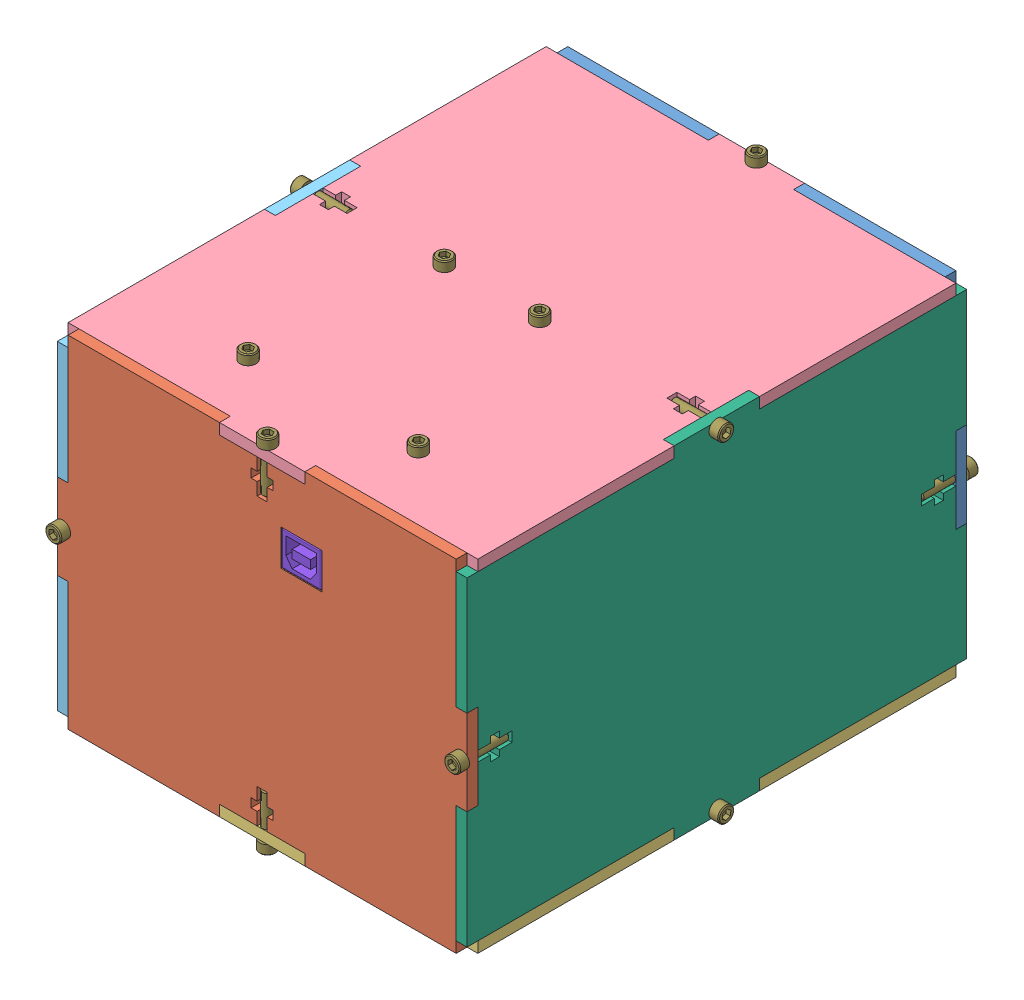
SolidWorks assembly PIDBoxAssem, configuration Default. Lengths in mm.
Overall size (127.39 117.77 152.04).
67 component instances, 23 part files, 145 mates.
Components (placement in the parent):
- PIDBoxFrontWall-1: PIDBoxFrontWall [Default] at (35.9834 39.6411 54.7935) size (120 100 3.17)
- PIDBoxBackWall-1: PIDBoxBackWall [Default] at (35.9834 39.6411 197.9685) size (120 100 3.17)
- PIDBoxTopWall-1: PIDBoxTopWall [Default] at (35.9834 -8.7714 126.381) x (0 0 -1) z (0 1 0) size (146.35 120 3.17)
- PIDBoxBottomWall-1: PIDBoxBottomWall [Default] at (35.9834 88.0536 126.381) x (0 0 1) z (0 -1 0) size (146.35 120 3.17)
- PIDBoxLeftWall-1: PIDBoxLeftWall [Default] at (-22.4291 39.6411 126.381) x (0 -1 0) z (-1 0 0) size (100 146.35 3.17)
- PIDBoxRightWall-1: PIDBoxRightWall [Default] at (94.3959 39.6411 126.381) x (0 1 0) z (-1 0 0) size (100 146.35 3.17)
- BatteryPack-1: BatteryPack [Default] at (-6.9166 43.4661 122.381) x (0 0 1) z (-1 0 0) size (104 66 18.8)
- ArduinoUno-1: ArduinoUno [Default] at (35.8084 73.7661 160.356) x (0 0 -1) z (-1 0 0) size (74.8 12.1 53.3)
- EE-SX672WR-1: EE-SX672WR [Default] at (60.4834 42.2161 69.081) x (0 0 -1) z (-1 0 0) size (13.7 38.4 26)
- MotorAssem-1: MotorAssem [Default] at (11.9922 -30.4605 140.9197) x (0 1 0) z (0 0 -1) size (63.22 63.17 37.75)
  - MotorMount-1: MotorMount [Default] at (15.7766 38.9912 50.9262) size (24 52.9 6)
  - DCmotor-Size130-1: DCmotor-Size130 [Default] at (36.7766 38.9912 34.9262) size (16.47 19.75 37.75)
  - socket head cap screw_ai-11: socket head cap screw_ai [HX-SHCS 0.112-40x0.625x0.625-N] at (50.1214 55.2437 53.9262) x (-1 0 0) z (0 0.924225 0.381849) size (18.72 4.65 4.65)
  - socket head cap screw_ai-12: socket head cap screw_ai [HX-SHCS 0.112-40x0.625x0.625-N] at (50.1214 22.7387 53.9262) x (-1 0 0) z (0 0.924225 0.381849) size (18.72 4.65 4.65)
  - InterruptWheel-1: InterruptWheel [Default] at (36.7766 38.9912 64.8387) x (0.948715 0.316133 0) z (0 0 1) size (50 49.92 3.17)
- 16x2 LCD Screen and Backpack-2: 16x2 LCD Screen and Backpack [Default] at (50.9834 -7.6283 151.1628) x (1 0 0) z (0 0 -1) size (80 20.27 36)
  - LCD_PCB-1: LCD_PCB [Default] at (-1.4055 -3.4444 3.0818) size (80 1.8 36)
  - metal_casing-1: metal_casing [Default] at (-1.5055 3.0556 3.5818) size (71.2 10.64 25.26)
  - LCDbacklight-1: LCDbacklight [Default] at (-1.7555 -3.4444 3.5818) size (74.7 3 18)
  - LCD-1: LCD [Default] at (-1.6055 1.9556 3.5818) size (70.3 2.1 22)
  - conductors-1: conductors [Default] at (-1.7555 -0.6944 13.8318) size (69.7 5.5 2.5)
  - conductors-2: conductors [Default] at (-1.7555 -0.6944 -6.6682) size (69.7 5.5 2.5)
  - LCD Backpack-1: LCD Backpack [Default] at (-14.7555 -9.9444 -4.3182) x (-1 0 0) z (0 -1 0) size (52 19.3 15.37)
- Panel Mount 10k Potentiometer-1: Panel Mount 10k Potentiometer [Default] at (50.9834 -7.1839 118.8352) x (0 -1 0) z (0 0 1) size (23.57 25.5 17)
- Panel Mount SPDT-1: Panel Mount SPDT [Default] at (74.1447 2.7261 102.731) x (-1 0 0) z (0 0 1) size (8 31.74 12.7)
- Panel Mount SPDT-2: Panel Mount SPDT [Default] at (27.8222 2.7261 102.731) x (-1 0 0) z (0 0 1) size (8 31.74 12.7)
- Panel Mount LED-2: Panel Mount LED [Default] at (-4.0166 -0.3589 156.381) x (-0.837169 0 -0.546944) z (-0.546944 0 0.837169) size (11.13 16 10.04)
- Panel Mount LED-3: Panel Mount LED [Default] at (-4.0166 -0.3589 136.381) x (-0.497225 0 -0.867621) z (-0.867621 0 0.497225) size (11.13 16 10.04)
- Panel Mount LED-4: Panel Mount LED [Default] at (-4.0166 -0.3589 116.381) x (-0.837169 0 -0.546944) z (-0.546944 0 0.837169) size (11.13 16 10.04)
- Panel Mount LED-5: Panel Mount LED [Default] at (-4.0166 -0.3589 96.381) x (-0.438178 0 -0.898888) z (-0.898888 0 0.438178) size (11.13 16 10.04)
- Panel Mount LED-6: Panel Mount LED [Default] at (-4.0166 -0.3589 76.381) x (-0.970279 0 -0.241991) z (-0.241991 0 0.970279) size (11.13 16 10.04)
- Panel Mount LED-9: Panel Mount LED [Default] at (74.1447 -0.3589 118.8352) x (-1 0 0) z (0 0 1) size (11.13 16 10.04)
- Panel Mount LED-10: Panel Mount LED [Default] at (27.8222 -0.3589 118.8352) x (-1 0 0) z (0 0 1) size (11.13 16 10.04)
- 25x.5 Aluminum Hex Female Female Standoff-1: 25x.5 Aluminum Hex Female Female Standoff [Default] at (40.5834 42.2161 62.731) x (0.999498 0.031674 0) z (0 0 1) size (6.35 8.06 12.7)
- 25x.5 Aluminum Hex Female Female Standoff-2: 25x.5 Aluminum Hex Female Female Standoff [Default] at (61.3834 42.2161 62.731) x (0.973982 0.226625 0) z (0 0 1) size (6.35 8.06 12.7)
- 25x.5 Aluminum Hex Female Female Standoff-3: 25x.5 Aluminum Hex Female Female Standoff [Default] at (11.6584 80.1161 179.356) x (1 0 0) z (0 -1 0) size (6.35 8.06 12.7)
- 25x.5 Aluminum Hex Female Female Standoff-4: 25x.5 Aluminum Hex Female Female Standoff [Default] at (16.7584 80.1161 126.956) x (1 0 0) z (0 -1 0) size (6.35 8.06 12.7)
- 25x.5 Aluminum Hex Female Female Standoff-5: 25x.5 Aluminum Hex Female Female Standoff [Default] at (44.6584 80.1161 126.956) x (1 0 0) z (0 -1 0) size (6.35 8.06 12.7)
- 25x.5 Aluminum Hex Female Female Standoff-7: 25x.5 Aluminum Hex Female Female Standoff [Default] at (59.9584 80.1161 177.756) x (1 0 0) z (0 -1 0) size (6.35 8.06 12.7)
- socket head cap screw_ai-3: socket head cap screw_ai [HX-SHCS 0.112-40x0.5x0.5-N] at (74.1447 -13.2037 86.9935) x (0 1 0) z (0 0 1) size (15.54 4.65 4.65)
- socket head cap screw_ai-4: socket head cap screw_ai [HX-SHCS 0.112-40x0.5x0.5-N] at (27.8222 -13.2037 86.9935) x (0 1 0) z (0 0 1) size (15.54 4.65 4.65)
- socket head cap screw_ai-2: socket head cap screw_ai [HX-SHCS 0.112-40x0.5x0.5-N] at (87.0779 -13.2037 163.581) x (0 1 0) z (0 0 1) size (15.54 4.65 4.65)
- socket head cap screw_ai-5: socket head cap screw_ai [HX-SHCS 0.112-40x0.5x0.5-N] at (87.0779 -13.2037 132.581) x (0 1 0) z (0 0 1) size (15.54 4.65 4.65)
- socket head cap screw_ai-6: socket head cap screw_ai [HX-SHCS 0.112-40x0.5x0.5-N] at (12.0779 -13.2037 132.581) x (0 1 0) z (0 0 1) size (15.54 4.65 4.65)
- socket head cap screw_ai-7: socket head cap screw_ai [HX-SHCS 0.112-40x0.5x0.5-N] at (12.0779 -13.2037 163.581) x (0 1 0) z (0 0 1) size (15.54 4.65 4.65)
- socket head cap screw_ai-9: socket head cap screw_ai [HX-SHCS 0.112-40x0.5x0.5-N] at (61.3834 42.2161 50.3612) x (0 0 1) z (-1 0 0) size (15.54 4.65 4.65)
- socket head cap screw_ai-10: socket head cap screw_ai [HX-SHCS 0.112-40x0.5x0.5-N] at (40.5834 42.2161 50.3612) x (0 0 1) z (-1 0 0) size (15.54 4.65 4.65)
- socket head cap screw_ai-11: socket head cap screw_ai [HX-SHCS 0.112-40x0.5x0.5-N] at (61.3834 42.2161 74.9258) x (0 0 -1) z (1 0 0) size (15.54 4.65 4.65)
- socket head cap screw_ai-12: socket head cap screw_ai [HX-SHCS 0.112-40x0.5x0.5-N] at (40.5834 42.2161 74.9258) x (0 0 -1) z (1 0 0) size (15.54 4.65 4.65)
- socket head cap screw_ai-17: socket head cap screw_ai [HX-SHCS 0.112-40x0.5x0.5-N] at (-28.5614 23.4661 175.381) size (15.54 4.65 4.65)
- socket head cap screw_ai-18: socket head cap screw_ai [HX-SHCS 0.112-40x0.5x0.5-N] at (-28.5614 63.4661 175.381) size (15.54 4.65 4.65)
- socket head cap screw_ai-20: socket head cap screw_ai [HX-SHCS 0.112-40x0.5x0.5-N] at (94.3959 39.6411 50.3612) x (0 0 1) z (-1 0 0) size (15.54 4.65 4.65)
- socket head cap screw_ai-21: socket head cap screw_ai [HX-SHCS 0.112-40x0.5x0.5-N] at (35.9834 -13.2037 54.7935) x (0 1 0) z (0 0 1) size (15.54 4.65 4.65)
- socket head cap screw_ai-22: socket head cap screw_ai [HX-SHCS 0.112-40x0.5x0.5-N] at (35.9834 92.4859 54.7935) x (0 -1 0) z (0 0 1) size (15.54 4.65 4.65)
- socket head cap screw_ai-23: socket head cap screw_ai [HX-SHCS 0.112-40x0.5x0.5-N] at (16.7584 92.4859 126.956) x (0 -1 0) z (0 0 1) size (15.54 4.65 4.65)
- socket head cap screw_ai-24: socket head cap screw_ai [HX-SHCS 0.112-40x0.5x0.5-N] at (44.6584 92.4859 126.956) x (0 -1 0) z (0 0 1) size (15.54 4.65 4.65)
- socket head cap screw_ai-25: socket head cap screw_ai [HX-SHCS 0.112-40x0.5x0.5-N] at (59.9584 92.4859 177.756) x (0 -1 0) z (0 0 1) size (15.54 4.65 4.65)
- socket head cap screw_ai-26: socket head cap screw_ai [HX-SHCS 0.112-40x0.5x0.5-N] at (11.6584 92.4859 179.356) x (0 -1 0) z (0 0 1) size (15.54 4.65 4.65)
- socket head cap screw_ai-27: socket head cap screw_ai [HX-SHCS 0.112-40x0.5x0.5-N] at (35.9834 92.4859 197.9685) x (0 -1 0) z (0 0 1) size (15.54 4.65 4.65)
- socket head cap screw_ai-28: socket head cap screw_ai [HX-SHCS 0.112-40x0.5x0.5-N] at (98.8282 88.0536 126.381) x (-1 0 0) z (0 0.924225 0.381849) size (15.54 4.65 4.65)
- socket head cap screw_ai-29: socket head cap screw_ai [HX-SHCS 0.112-40x0.5x0.5-N] at (98.8282 -8.7714 126.381) x (-1 0 0) z (0 0.924225 0.381849) size (15.54 4.65 4.65)
- socket head cap screw_ai-30: socket head cap screw_ai [HX-SHCS 0.112-40x0.5x0.5-N] at (94.3959 39.6411 202.4008) x (0 0 -1) z (1 0 0) size (15.54 4.65 4.65)
- socket head cap screw_ai-31: socket head cap screw_ai [HX-SHCS 0.112-40x0.5x0.5-N] at (35.9834 -13.2037 197.9685) x (0 1 0) z (0 0 1) size (15.54 4.65 4.65)
- socket head cap screw_ai-32: socket head cap screw_ai [HX-SHCS 0.112-40x0.5x0.5-N] at (-22.4291 39.6411 202.4008) x (0 0 -1) z (1 0 0) size (15.54 4.65 4.65)
- socket head cap screw_ai-33: socket head cap screw_ai [HX-SHCS 0.112-40x0.5x0.5-N] at (-26.8614 88.0536 126.381) size (15.54 4.65 4.65)
- socket head cap screw_ai-34: socket head cap screw_ai [HX-SHCS 0.112-40x0.5x0.5-N] at (-26.8614 -8.7714 126.381) size (15.54 4.65 4.65)
- socket head cap screw_ai-35: socket head cap screw_ai [HX-SHCS 0.112-40x0.5x0.5-N] at (-22.4291 39.6411 50.3612) x (0 0 1) z (-1 0 0) size (15.54 4.65 4.65)
Mates (geometry in assembly coordinates):
- Coincident1: coincident aligned: plane of PIDBoxWall1-1 through (35.9834 39.6411 53.206) normal (0 0 -1); plane of PIDBoxTopWall-1 through (23.4834 -7.1839 53.206) normal (0 0 -1)
- Parallel1: parallel aligned: plane of PIDBoxWall1-1 through (35.9834 89.6411 56.381) normal (0 1 0); plane of PIDBoxTopWall-1 through (35.9834 -7.1839 126.381) normal (0 1 0)
- Coincident3: coincident aligned: line of PIDBoxWall1-1 through (48.4834 -10.3589 56.381) axis (1 0 0); line of PIDBoxTopWall-1 through (48.4834 -10.3589 56.381) axis (1 0 0)
- Coincident4: coincident: line of PIDBoxWall1-1 through (23.4834 -7.1839 56.381) axis (0 0 -1); plane of PIDBoxTopWall-1 through (23.4834 -7.1839 53.206) normal (-1 0 0)
- Coincident5: coincident anti-aligned: plane of PIDBoxTopWall-1 through (35.9834 -7.1839 126.381) normal (0 1 0); plane of MotorAssem-1/MotorMount-1 through (50.9834 -7.1839 89.9935) normal (0 -1 0)
- Distance3: distance = 15 mm anti-aligned: plane of PIDBoxTopWall-1 through (35.9834 -8.7714 126.381) normal (-1 0 0); plane of MotorAssem-1/DCmotor-Size130-1 through (50.9834 6.3161 105.9935) normal (1 0 0)
- Parallel2: parallel anti-aligned: plane of PIDBoxTopWall-1 through (35.9834 -10.3589 126.381) normal (0 -1 0); plane of EE-SX672WR-1 through (47.8084 52.5161 73.581) normal (0 1 0)
- Distance4: distance = 15 mm: point of PIDBoxWall1-1; moEndPointRef_w of EE-SX672WR-1
- Concentric1: concentric aligned: circle of 25x.5 Aluminum Hex Female Female Standoff-1; circle of EE-SX672WR-1
- Coincident10: coincident anti-aligned: plane of EE-SX672WR-1 through (60.4834 42.2161 69.081) normal (0 0 -1); plane of 25x.5 Aluminum Hex Female Female Standoff-1 through (40.5834 42.2161 69.081) normal (0 0 1)
- Coincident11: coincident anti-aligned: plane of PIDBoxWall1-1 through (35.9834 39.6411 56.381) normal (0 0 1); plane of 25x.5 Aluminum Hex Female Female Standoff-1 through (40.5834 42.2161 56.381) normal (0 0 -1)
- Concentric2: concentric aligned: circle of EE-SX672WR-1; circle of 25x.5 Aluminum Hex Female Female Standoff-2
- Coincident12: coincident anti-aligned: plane of EE-SX672WR-1 through (60.4834 42.2161 69.081) normal (0 0 -1); plane of 25x.5 Aluminum Hex Female Female Standoff-2 through (61.3834 42.2161 69.081) normal (0 0 1)
- Coincident17: coincident: plane of MotorAssem-1/InterruptWheel-1 through (50.9834 6.3161 76.081) normal (0 0 -1); line of EE-SX672WR-1 through (54.1584 35.3161 76.081) axis (0 1 0)
- Distance1: distance = 4 mm anti-aligned: plane of EE-SX672WR-1 through (54.1584 35.3161 78.581) normal (0 -1 0); cylinder of MotorAssem-1/InterruptWheel-1 through (50.9834 6.3161 74.4935) axis (0 0 1) radius 25
- Coincident24: coincident anti-aligned: plane of PIDBoxTopWall-1 through (35.9834 -7.1839 126.381) normal (0 1 0); plane of 16x2 LCD Screen and Backpack-2/LCDbacklight-1 through (49.2279 -7.1839 147.581) normal (0 -1 0)
- Parallel7: parallel anti-aligned: plane of PIDBoxWall1-1 through (35.9834 39.6411 56.381) normal (0 0 1); plane of 16x2 LCD Screen and Backpack-2/LCD_PCB-1 through (89.5779 -2.5839 130.081) normal (0 0 -1)
- Distance6: distance = 15 mm aligned: plane of PIDBoxWall1-1 through (35.9834 39.6411 54.7935) normal (1 0 0); plane of 16x2 LCD Screen and Backpack-2 through (50.9834 -7.6283 151.1628) normal (1 0 0)
- Distance2: distance = 50 mm aligned: plane of 16x2 LCD Screen and Backpack-2/LCD_PCB-1 through (89.5779 -2.5839 130.081) normal (0 0 -1); plane of PIDBoxTopWall-1 through (28.4834 -7.1839 80.081) normal (0 0 -1)
- Parallel8: parallel anti-aligned: plane of PIDBoxTopWall-1 through (35.9834 -10.3589 126.381) normal (0 -1 0); plane of Panel Mount 10k Potentiometer-1 through (50.9834 0.3161 118.8352) normal (0 1 0)
- Parallel9: parallel aligned: plane of PIDBoxWall1-1 through (35.9834 39.6411 53.206) normal (0 0 -1); plane of Panel Mount 10k Potentiometer-1 through (47.7334 -16.6839 113.206) normal (0 0 -1)
- Distance5: distance = 15 mm anti-aligned: plane of PIDBoxTopWall-1 through (35.9834 -8.7714 126.381) normal (-1 0 0); plane of Panel Mount 10k Potentiometer-1 through (50.9834 -7.1839 118.8352) normal (1 0 0)
- Coincident30: coincident anti-aligned: plane of PIDBoxTopWall-1 through (35.9834 -7.1839 126.381) normal (0 1 0); plane of Panel Mount 10k Potentiometer-1 through (50.9834 -7.1839 118.8352) normal (0 -1 0)
- Concentric3: concentric anti-aligned: circle of PIDBoxWall2-1; cylinder of Panel Mount LED-2 through (-4.0166 -0.3589 156.381) axis (0 1 0) radius 3.937
- Coincident34: coincident anti-aligned: plane of PIDBoxTopWall-1 through (35.9834 -10.3589 126.381) normal (0 -1 0); plane of Panel Mount LED-2 through (-8.2198 -10.3589 153.635) normal (0 1 0)
- Concentric4: concentric anti-aligned: cylinder of PIDBoxTopWall-1 through (-4.0166 -7.1839 136.381) axis (0 -1 0) radius 4; cylinder of Panel Mount LED-3 through (-4.0166 -0.3589 136.381) axis (0 1 0) radius 3.937
- Coincident35: coincident anti-aligned: plane of PIDBoxTopWall-1 through (35.9834 -10.3589 126.381) normal (0 -1 0); plane of Panel Mount LED-3 through (-6.513 -10.3589 132.025) normal (0 1 0)
- Coincident38: coincident anti-aligned: plane of PIDBoxTopWall-1 through (35.9834 -10.3589 126.381) normal (0 -1 0); plane of Panel Mount LED-4 through (-8.2198 -10.3589 113.635) normal (0 1 0)
- Coincident39: coincident anti-aligned: plane of PIDBoxTopWall-1 through (35.9834 -10.3589 126.381) normal (0 -1 0); plane of Panel Mount LED-5 through (-6.2166 -10.3589 91.868) normal (0 1 0)
- Concentric5: concentric anti-aligned: cylinder of PIDBoxTopWall-1 through (-4.0166 -7.1839 116.381) axis (0 -1 0) radius 4; cylinder of Panel Mount LED-4 through (-4.0166 -0.3589 116.381) axis (0 1 0) radius 3.937
- Concentric6: concentric anti-aligned: cylinder of PIDBoxTopWall-1 through (-4.0166 -7.1839 96.381) axis (0 -1 0) radius 4; cylinder of Panel Mount LED-5 through (-4.0166 -0.3589 96.381) axis (0 1 0) radius 3.937
- Coincident40: coincident anti-aligned: plane of PIDBoxTopWall-1 through (35.9834 -10.3589 126.381) normal (0 -1 0); plane of Panel Mount LED-6 through (-8.8881 -10.3589 75.1661) normal (0 1 0)
- Concentric7: concentric anti-aligned: cylinder of PIDBoxTopWall-1 through (-4.0166 -7.1839 76.381) axis (0 -1 0) radius 4; cylinder of Panel Mount LED-6 through (-4.0166 -0.3589 76.381) axis (0 1 0) radius 3.937
- Distance7: distance = 60 mm aligned: plane of Panel Mount 10k Potentiometer-1 through (47.7334 -16.6839 113.206) normal (0 0 -1); plane of PIDBoxWall1-1 through (35.9834 39.6411 53.206) normal (0 0 -1)
- Concentric8: concentric anti-aligned: cylinder of PIDBoxTopWall-1 through (87.0779 -10.3589 163.581) axis (0 1 0) radius 1.25; cylinder of socket head cap screw_ai-2 through (87.0779 -44.9537 163.581) axis (0 -1 0) radius 2.3241
- Coincident41: coincident anti-aligned: plane of PIDBoxTopWall-1 through (35.9834 -10.3589 126.381) normal (0 -1 0); plane of socket head cap screw_ai-2 through (84.7538 -10.3589 163.581) normal (0 1 0)
- Concentric9: concentric anti-aligned: cylinder of PIDBoxTopWall-1 through (74.1447 -10.3589 86.9935) axis (0 1 0) radius 1.47; cylinder of socket head cap screw_ai-3 through (74.1447 -44.9537 86.9935) axis (0 -1 0) radius 2.3241
- Coincident42: coincident anti-aligned: plane of PIDBoxTopWall-1 through (35.9834 -10.3589 126.381) normal (0 -1 0); plane of socket head cap screw_ai-3 through (71.8206 -10.3589 86.9935) normal (0 1 0)
- Concentric10: concentric anti-aligned: cylinder of PIDBoxTopWall-1 through (27.8222 -10.3589 86.9935) axis (0 1 0) radius 1.47; cylinder of socket head cap screw_ai-4 through (27.8222 -44.9537 86.9935) axis (0 -1 0) radius 2.3241
- Coincident43: coincident anti-aligned: plane of PIDBoxTopWall-1 through (35.9834 -10.3589 126.381) normal (0 -1 0); plane of socket head cap screw_ai-4 through (25.4981 -10.3589 86.9935) normal (0 1 0)
- Concentric11: concentric anti-aligned: cylinder of PIDBoxTopWall-1 through (87.0779 -10.3589 132.581) axis (0 1 0) radius 1.25; cylinder of socket head cap screw_ai-5 through (87.0779 -44.9537 132.581) axis (0 -1 0) radius 2.3241
- Coincident44: coincident anti-aligned: plane of PIDBoxTopWall-1 through (35.9834 -10.3589 126.381) normal (0 -1 0); plane of socket head cap screw_ai-5 through (84.7538 -10.3589 132.581) normal (0 1 0)
- Concentric12: concentric anti-aligned: cylinder of PIDBoxTopWall-1 through (12.0779 -10.3589 132.581) axis (0 1 0) radius 1.25; cylinder of socket head cap screw_ai-6 through (12.0779 -44.9537 132.581) axis (0 -1 0) radius 2.3241
- Coincident45: coincident anti-aligned: plane of PIDBoxTopWall-1 through (35.9834 -10.3589 126.381) normal (0 -1 0); plane of socket head cap screw_ai-6 through (9.7538 -10.3589 132.581) normal (0 1 0)
- Concentric13: concentric anti-aligned: cylinder of PIDBoxTopWall-1 through (12.0779 -10.3589 163.581) axis (0 1 0) radius 1.25; cylinder of socket head cap screw_ai-7 through (12.0779 -44.9537 163.581) axis (0 -1 0) radius 2.3241
- Coincident46: coincident anti-aligned: plane of PIDBoxTopWall-1 through (35.9834 -10.3589 126.381) normal (0 -1 0); plane of socket head cap screw_ai-7 through (9.7538 -10.3589 163.581) normal (0 1 0)
- Coincident47: coincident anti-aligned: plane of PIDBoxTopWall-1 through (35.9834 -7.1839 126.381) normal (0 1 0); plane of Panel Mount SPDT-1 through (74.1447 -7.1839 102.731) normal (0 -1 0)
- Parallel10: parallel aligned: plane of PIDBoxWall1-1 through (35.9834 39.6411 56.381) normal (0 0 1); plane of Panel Mount SPDT-1 through (77.5747 -6.1639 109.081) normal (0 0 1)
- Coincident49: coincident anti-aligned: plane of PIDBoxTopWall-1 through (35.9834 -7.1839 126.381) normal (0 1 0); plane of Panel Mount SPDT-2 through (27.8222 -7.1839 102.731) normal (0 -1 0)
- Parallel11: parallel anti-aligned: plane of PIDBoxWall1-1 through (35.9834 39.6411 56.381) normal (0 0 1); plane of Panel Mount SPDT-2 through (31.2522 -6.1639 96.381) normal (0 0 -1)
- Coincident52: coincident: plane of Panel Mount SPDT-2 through (27.8222 2.7261 102.731) normal (-1 0 0)
- Coincident53: coincident: plane of Panel Mount SPDT-1 through (74.1447 2.7261 102.731) normal (-1 0 0)
- Distance8: distance = 40 mm anti-aligned: plane of Panel Mount SPDT-2 through (31.2522 -6.1639 96.381) normal (0 0 -1); plane of PIDBoxWall1-1 through (35.9834 39.6411 56.381) normal (0 0 1)
- Coincident55: coincident aligned: plane of Panel Mount SPDT-1 through (77.5747 -6.1639 96.381) normal (0 0 -1); plane of Panel Mount SPDT-2 through (31.2522 -6.1639 96.381) normal (0 0 -1)
- Coincident56: coincident aligned: plane of Panel Mount SPDT-2 through (27.8222 2.7261 102.731) normal (-1 0 0); plane of Panel Mount LED-10 through (27.8222 -0.3589 118.8352) normal (-1 0 0)
- Coincident57: coincident aligned: plane of Panel Mount SPDT-1 through (74.1447 2.7261 102.731) normal (-1 0 0); plane of Panel Mount LED-9 through (74.1447 -0.3589 118.8352) normal (-1 0 0)
- Coincident58: coincident anti-aligned: plane of PIDBoxTopWall-1 through (35.9834 -10.3589 126.381) normal (0 -1 0); plane of Panel Mount LED-10 through (22.8015 -10.3589 118.8352) normal (0 1 0)
- Coincident59: coincident anti-aligned: plane of PIDBoxTopWall-1 through (35.9834 -10.3589 126.381) normal (0 -1 0); plane of Panel Mount LED-9 through (69.124 -10.3589 118.8352) normal (0 1 0)
- Coincident60: coincident aligned: plane of Panel Mount LED-9 through (74.1447 -0.3589 118.8352) normal (0 0 1); plane of Panel Mount 10k Potentiometer-1 through (50.9834 -7.1839 118.8352) normal (0 0 1)
- Coincident61: coincident aligned: plane of Panel Mount 10k Potentiometer-1 through (50.9834 -7.1839 118.8352) normal (0 0 1); plane of Panel Mount LED-10 through (27.8222 -0.3589 118.8352) normal (0 0 1)
- Concentric14: concentric aligned: cylinder of PIDBoxWall1-1 through (61.3834 42.2161 56.381) axis (0 0 -1) radius 1.0287; cylinder of socket head cap screw_ai-9 through (61.3834 42.2161 18.6112) axis (0 0 -1) radius 2.3241
- Coincident62: coincident anti-aligned: plane of PIDBoxWall1-1 through (35.9834 39.6411 53.206) normal (0 0 -1); plane of socket head cap screw_ai-9 through (61.3834 44.5402 53.206) normal (0 0 1)
- Concentric151: concentric aligned: cylinder of PIDBoxWall1-1 through (40.5834 42.2161 56.381) axis (0 0 -1) radius 1.0287; cylinder of socket head cap screw_ai-10 through (40.5834 42.2161 18.6112) axis (0 0 -1) radius 2.3241
- Coincident631: coincident anti-aligned: plane of PIDBoxWall1-1 through (35.9834 39.6411 53.206) normal (0 0 -1); plane of socket head cap screw_ai-10 through (40.5834 44.5402 53.206) normal (0 0 1)
- Concentric16: concentric anti-aligned: cylinder of EE-SX672WR-1 through (61.3834 42.2161 82.781) axis (0 0 -1) radius 1.6; cylinder of socket head cap screw_ai-11 through (61.3834 42.2161 106.6758) axis (0 0 1) radius 2.3241
- Coincident64: coincident anti-aligned: plane of EE-SX672WR-1 through (63.9834 39.1161 72.081) normal (0 0 1); plane of socket head cap screw_ai-11 through (61.3834 44.5402 72.081) normal (0 0 -1)
- Concentric17: concentric aligned: cylinder of EE-SX672WR-1 through (40.5834 42.2161 69.081) axis (0 0 1) radius 1.6; cylinder of socket head cap screw_ai-12 through (40.5834 42.2161 106.6758) axis (0 0 1) radius 2.3241
- Coincident65: coincident anti-aligned: plane of EE-SX672WR-1 through (37.9834 45.3161 72.081) normal (0 0 1); plane of socket head cap screw_ai-12 through (40.5834 44.5402 72.081) normal (0 0 -1)
- Coincident66: coincident anti-aligned: plane of PIDBoxWall1-1 through (35.9834 39.6411 56.381) normal (0 0 1); plane of PIDBoxBottomWall-1 through (35.9834 86.4661 56.381) normal (0 0 -1)
- Coincident67: coincident anti-aligned: line of PIDBoxWall1-1 through (34.5134 86.4661 53.206) axis (-1 0 0); line of PIDBoxBottomWall-1 through (23.4834 86.4661 53.206) axis (1 0 0)
- Coincident68: coincident anti-aligned: plane of PIDBoxWall1-1 through (48.4834 39.6411 56.381) normal (-1 0 0); plane of PIDBoxBottomWall-1 through (48.4834 86.4661 53.206) normal (1 0 0)
- Parallel12: parallel anti-aligned: plane of PIDBoxBottomWall-1 through (35.9834 86.4661 126.381) normal (0 -1 0); plane of ArduinoUno-1 through (62.4584 73.7661 127.356) normal (0 1 0)
- Concentric18: concentric anti-aligned: circle of ArduinoUno-1; circle of 25x.5 Aluminum Hex Female Female Standoff-3
- Coincident70: coincident anti-aligned: plane of ArduinoUno-1 through (62.4584 73.7661 127.356) normal (0 1 0); plane of 25x.5 Aluminum Hex Female Female Standoff-3 through (11.6584 73.7661 179.356) normal (0 -1 0)
- Coincident71: coincident aligned: circle of ArduinoUno-1; plane of 25x.5 Aluminum Hex Female Female Standoff-4 through (16.7584 73.7661 126.956) normal (0 -1 0)
- Concentric19: concentric aligned: circle of ArduinoUno-1; circle of 25x.5 Aluminum Hex Female Female Standoff-4
- Coincident72: coincident anti-aligned: plane of ArduinoUno-1 through (62.4584 73.7661 127.356) normal (0 1 0); plane of 25x.5 Aluminum Hex Female Female Standoff-5 through (44.6584 73.7661 126.956) normal (0 -1 0)
- Concentric20: concentric anti-aligned: circle of ArduinoUno-1; circle of 25x.5 Aluminum Hex Female Female Standoff-5
- Coincident74: coincident anti-aligned: plane of ArduinoUno-1 through (62.4584 73.7661 127.356) normal (0 1 0); plane of 25x.5 Aluminum Hex Female Female Standoff-7 through (59.9584 73.7661 177.756) normal (0 -1 0)
- Concentric22: concentric aligned: circle of ArduinoUno-1; circle of 25x.5 Aluminum Hex Female Female Standoff-7
- Coincident632: coincident aligned: plane of PIDBoxTopWall-1 through (23.4834 -7.1839 199.556) normal (0 0 1); plane of PIDBoxBackWall-1 through (35.9834 39.6411 199.556) normal (0 0 1)
- Coincident633: coincident anti-aligned: plane of PIDBoxBottomWall-1 through (48.4834 86.4661 199.556) normal (1 0 0); plane of PIDBoxBackWall-1 through (48.4834 39.6411 199.556) normal (-1 0 0)
- Coincident634: coincident anti-aligned: plane of PIDBoxBottomWall-1 through (35.9834 86.4661 126.381) normal (0 -1 0); plane of PIDBoxBackWall-1 through (35.9834 86.4661 199.556) normal (0 1 0)
- Distance10: distance = 10 mm anti-aligned: plane of PIDBoxBottomWall-1 through (35.9834 86.4661 126.381) normal (0 -1 0); plane of BatteryPack-1 through (-24.0166 76.4661 74.381) normal (0 1 0)
- Coincident644: coincident aligned: plane of PIDBoxTopWall-1 through (35.9834 -10.3589 126.381) normal (0 -1 0); plane of PIDBoxRightWall-1 through (92.8084 -10.3589 113.881) normal (0 -1 0)
- Coincident645: coincident anti-aligned: plane of PIDBoxTopWall-1 through (92.8084 -7.1839 126.381) normal (1 0 0); plane of PIDBoxRightWall-1 through (92.8084 39.6411 126.381) normal (-1 0 0)
- Coincident646: coincident anti-aligned: plane of PIDBoxFrontWall-1 through (35.9834 39.6411 56.381) normal (0 0 1); plane of PIDBoxRightWall-1 through (92.8084 39.6411 56.381) normal (0 0 -1)
- Coincident647: coincident aligned: plane of PIDBoxBottomWall-1 through (35.9834 89.6411 126.381) normal (0 1 0); plane of PIDBoxLeftWall-1 through (-24.0166 89.6411 138.881) normal (0 1 0)
- Coincident648: coincident aligned: plane of PIDBoxFrontWall-1 through (-24.0166 52.1411 56.381) normal (-1 0 0); plane of PIDBoxLeftWall-1 through (-24.0166 39.6411 126.381) normal (-1 0 0)
- Coincident649: coincident anti-aligned: plane of PIDBoxBackWall-1 through (35.9834 39.6411 196.381) normal (0 0 -1); plane of PIDBoxLeftWall-1 through (-24.0166 39.6411 196.381) normal (0 0 1)
- Coincident650: coincident anti-aligned: plane of PIDBoxLeftWall-1 through (-24.0166 39.6411 126.381) normal (-1 0 0); plane of BatteryPack-1 through (-24.0166 14.4661 174.381) normal (1 0 0)
- Concentric154: concentric aligned: cylinder of BatteryPack-1 through (-6.9166 23.4661 175.381) axis (-1 0 0) radius 1.47; cylinder of socket head cap screw_ai-17 through (-60.3114 23.4661 175.381) axis (-1 0 0) radius 2.3241
- Coincident654: coincident anti-aligned: plane of BatteryPack-1 through (-25.7166 14.4661 174.381) normal (-1 0 0); plane of socket head cap screw_ai-17 through (-25.7166 25.7902 175.381) normal (1 0 0)
- Concentric155: concentric aligned: cylinder of BatteryPack-1 through (-6.9166 63.4661 175.381) axis (-1 0 0) radius 1.47; cylinder of socket head cap screw_ai-18 through (-60.3114 63.4661 175.381) axis (-1 0 0) radius 2.3241
- Coincident655: coincident anti-aligned: plane of BatteryPack-1 through (-25.7166 14.4661 174.381) normal (-1 0 0); plane of socket head cap screw_ai-18 through (-25.7166 65.7902 175.381) normal (1 0 0)
- Distance11: distance = 18 mm anti-aligned: plane of PIDBoxFrontWall-1 through (35.9834 39.6411 56.381) normal (0 0 1); plane of BatteryPack-1 through (-24.0166 10.4661 74.381) normal (0 0 -1)
- Distance12: distance = 10 mm: plane of PIDBoxBottomWall-1 through (35.9834 86.4661 126.381) normal (0 -1 0); plane of MotorAssem-1/BatteryPack-1 through (-24.0166 76.4661 74.381) normal (0 1 0)
- Coincident657: coincident: plane of PIDBoxLeftWall-1 through (-24.0166 39.6411 126.381) normal (-1 0 0); plane of MotorAssem-1/BatteryPack-1 through (-24.0166 14.4661 174.381) normal (1 0 0)
- Concentric156: concentric aligned: cylinder of MotorAssem-1/BatteryPack-1 through (-6.9166 23.4661 175.381) axis (-1 0 0) radius 1.47; cylinder of socket head cap screw_ai-17 through (-60.3114 23.4661 175.381) axis (-1 0 0) radius 2.3241
- Coincident658: coincident anti-aligned: plane of MotorAssem-1/BatteryPack-1 through (-25.7166 14.4661 174.381) normal (-1 0 0); plane of socket head cap screw_ai-17 through (-25.7166 25.7902 175.381) normal (1 0 0)
- Concentric157: concentric aligned: cylinder of MotorAssem-1/BatteryPack-1 through (-6.9166 63.4661 175.381) axis (-1 0 0) radius 1.47; cylinder of socket head cap screw_ai-18 through (-60.3114 63.4661 175.381) axis (-1 0 0) radius 2.3241
- Coincident659: coincident anti-aligned: plane of MotorAssem-1/BatteryPack-1 through (-25.7166 14.4661 174.381) normal (-1 0 0); plane of socket head cap screw_ai-18 through (-25.7166 65.7902 175.381) normal (1 0 0)
- Distance13: distance = 18 mm: plane of PIDBoxFrontWall-1 through (35.9834 39.6411 56.381) normal (0 0 1); plane of MotorAssem-1/BatteryPack-1 through (-24.0166 10.4661 74.381) normal (0 0 -1)
- Distance14: distance = 10 mm: plane of PIDBoxBottomWall-1 through (35.9834 86.4661 126.381) normal (0 -1 0); plane of MotorAssem-1/BatteryPack-2 through (-24.0166 76.4661 74.381) normal (0 1 0)
- Coincident660: coincident: plane of PIDBoxLeftWall-1 through (-24.0166 39.6411 126.381) normal (-1 0 0); plane of MotorAssem-1/BatteryPack-2 through (-24.0166 14.4661 174.381) normal (1 0 0)
- Concentric158: concentric aligned: cylinder of MotorAssem-1/BatteryPack-2 through (-6.9166 23.4661 175.381) axis (-1 0 0) radius 1.47; cylinder of socket head cap screw_ai-17 through (-60.3114 23.4661 175.381) axis (-1 0 0) radius 2.3241
- Coincident661: coincident anti-aligned: plane of MotorAssem-1/BatteryPack-2 through (-25.7166 14.4661 174.381) normal (-1 0 0); plane of socket head cap screw_ai-17 through (-25.7166 25.7902 175.381) normal (1 0 0)
- Concentric159: concentric aligned: cylinder of MotorAssem-1/BatteryPack-2 through (-6.9166 63.4661 175.381) axis (-1 0 0) radius 1.47; cylinder of socket head cap screw_ai-18 through (-60.3114 63.4661 175.381) axis (-1 0 0) radius 2.3241
- Coincident662: coincident anti-aligned: plane of MotorAssem-1/BatteryPack-2 through (-25.7166 14.4661 174.381) normal (-1 0 0); plane of socket head cap screw_ai-18 through (-25.7166 65.7902 175.381) normal (1 0 0)
- Distance15: distance = 18 mm: plane of PIDBoxFrontWall-1 through (35.9834 39.6411 56.381) normal (0 0 1); plane of MotorAssem-1/BatteryPack-2 through (-24.0166 10.4661 74.381) normal (0 0 -1)
- Coincident663: coincident anti-aligned: plane of PIDBoxBottomWall-1 through (35.9834 86.4661 126.381) normal (0 -1 0); plane of 25x.5 Aluminum Hex Female Female Standoff-3 through (11.6584 86.4661 179.356) normal (0 1 0)
- Coincident668: coincident aligned: plane of PIDBoxBackWall-1 through (35.9834 39.6411 199.556) normal (0 0 1); plane of ArduinoUno-1 through (53.4584 61.6661 199.556) normal (0 0 1)
- Distance16: distance = 30 mm anti-aligned: plane of ArduinoUno-1 through (9.1584 72.1661 127.356) normal (-1 0 0); plane of PIDBoxLeftWall-1 through (-20.8416 39.6411 126.381) normal (1 0 0)
- Concentric160: concentric aligned: cylinder of PIDBoxFrontWall-1 through (94.3959 39.6411 56.381) axis (0 0 -1) radius 1.47; cylinder of socket head cap screw_ai-20 through (94.3959 39.6411 18.6112) axis (0 0 -1) radius 2.3241
- Coincident669: coincident anti-aligned: plane of PIDBoxFrontWall-1 through (35.9834 39.6411 53.206) normal (0 0 -1); plane of socket head cap screw_ai-20 through (94.3959 41.9652 53.206) normal (0 0 1)
- Concentric161: concentric aligned: cylinder of PIDBoxTopWall-1 through (35.9834 -7.1839 54.7935) axis (0 -1 0) radius 1.47; cylinder of socket head cap screw_ai-21 through (35.9834 -44.9537 54.7935) axis (0 -1 0) radius 2.3241
- Coincident670: coincident anti-aligned: plane of PIDBoxTopWall-1 through (35.9834 -10.3589 126.381) normal (0 -1 0); plane of socket head cap screw_ai-21 through (33.6593 -10.3589 54.7935) normal (0 1 0)
- Concentric162: concentric aligned: cylinder of PIDBoxBottomWall-1 through (35.9834 86.4661 54.7935) axis (0 1 0) radius 1.47; cylinder of socket head cap screw_ai-22 through (35.9834 124.2359 54.7935) axis (0 1 0) radius 2.3241
- Coincident671: coincident anti-aligned: plane of PIDBoxBottomWall-1 through (35.9834 89.6411 126.381) normal (0 1 0); plane of socket head cap screw_ai-22 through (38.3075 89.6411 54.7935) normal (0 -1 0)
- Concentric163: concentric aligned: cylinder of PIDBoxBottomWall-1 through (16.7584 86.4661 126.956) axis (0 1 0) radius 1.0287; cylinder of socket head cap screw_ai-23 through (16.7584 124.2359 126.956) axis (0 1 0) radius 2.3241
- Coincident672: coincident anti-aligned: plane of PIDBoxBottomWall-1 through (35.9834 89.6411 126.381) normal (0 1 0); plane of socket head cap screw_ai-23 through (19.0825 89.6411 126.956) normal (0 -1 0)
- Concentric164: concentric aligned: cylinder of PIDBoxBottomWall-1 through (44.6584 86.4661 126.956) axis (0 1 0) radius 1.0287; cylinder of socket head cap screw_ai-24 through (44.6584 124.2359 126.956) axis (0 1 0) radius 2.3241
- Coincident673: coincident anti-aligned: plane of PIDBoxBottomWall-1 through (35.9834 89.6411 126.381) normal (0 1 0); plane of socket head cap screw_ai-24 through (46.9825 89.6411 126.956) normal (0 -1 0)
- Concentric165: concentric aligned: cylinder of PIDBoxBottomWall-1 through (59.9584 86.4661 177.756) axis (0 1 0) radius 1.0287; cylinder of socket head cap screw_ai-25 through (59.9584 124.2359 177.756) axis (0 1 0) radius 2.3241
- Coincident674: coincident anti-aligned: plane of PIDBoxBottomWall-1 through (35.9834 89.6411 126.381) normal (0 1 0); plane of socket head cap screw_ai-25 through (62.2825 89.6411 177.756) normal (0 -1 0)
- Concentric166: concentric aligned: cylinder of PIDBoxBottomWall-1 through (11.6584 86.4661 179.356) axis (0 1 0) radius 1.0287; cylinder of socket head cap screw_ai-26 through (11.6584 124.2359 179.356) axis (0 1 0) radius 2.3241
- Coincident675: coincident anti-aligned: plane of PIDBoxBottomWall-1 through (35.9834 89.6411 126.381) normal (0 1 0); plane of socket head cap screw_ai-26 through (13.9825 89.6411 179.356) normal (0 -1 0)
- Concentric167: concentric aligned: cylinder of PIDBoxBottomWall-1 through (35.9834 86.4661 197.9685) axis (0 1 0) radius 1.47; cylinder of socket head cap screw_ai-27 through (35.9834 124.2359 197.9685) axis (0 1 0) radius 2.3241
- Coincident676: coincident anti-aligned: plane of PIDBoxBottomWall-1 through (35.9834 89.6411 126.381) normal (0 1 0); plane of socket head cap screw_ai-27 through (38.3075 89.6411 197.9685) normal (0 -1 0)
- Concentric168: concentric aligned: cylinder of PIDBoxRightWall-1 through (92.8084 88.0536 126.381) axis (1 0 0) radius 1.47; cylinder of socket head cap screw_ai-28 through (130.5782 88.0536 126.381) axis (1 0 0) radius 2.3241
- Coincident677: coincident anti-aligned: plane of PIDBoxRightWall-1 through (95.9834 39.6411 126.381) normal (1 0 0); plane of socket head cap screw_ai-28 through (95.9834 87.1661 128.529) normal (-1 0 0)
- Concentric169: concentric aligned: cylinder of PIDBoxRightWall-1 through (92.8084 -8.7714 126.381) axis (1 0 0) radius 1.47; cylinder of socket head cap screw_ai-29 through (130.5782 -8.7714 126.381) axis (1 0 0) radius 2.3241
- Coincident678: coincident anti-aligned: plane of PIDBoxRightWall-1 through (95.9834 39.6411 126.381) normal (1 0 0); plane of socket head cap screw_ai-29 through (95.9834 -9.6589 128.529) normal (-1 0 0)
- Concentric170: concentric anti-aligned: cylinder of PIDBoxBackWall-1 through (94.3959 39.6411 199.556) axis (0 0 -1) radius 1.47; cylinder of socket head cap screw_ai-30 through (94.3959 39.6411 234.1508) axis (0 0 1) radius 2.3241
- Coincident679: coincident anti-aligned: plane of PIDBoxBackWall-1 through (35.9834 39.6411 199.556) normal (0 0 1); plane of socket head cap screw_ai-30 through (94.3959 41.9652 199.556) normal (0 0 -1)
- Concentric171: concentric aligned: cylinder of PIDBoxTopWall-1 through (35.9834 -7.1839 197.9685) axis (0 -1 0) radius 1.47; cylinder of socket head cap screw_ai-31 through (35.9834 -44.9537 197.9685) axis (0 -1 0) radius 2.3241
- Coincident680: coincident anti-aligned: plane of PIDBoxTopWall-1 through (35.9834 -10.3589 126.381) normal (0 -1 0); plane of socket head cap screw_ai-31 through (33.6593 -10.3589 197.9685) normal (0 1 0)
- Concentric172: concentric anti-aligned: cylinder of PIDBoxBackWall-1 through (-22.4291 39.6411 199.556) axis (0 0 -1) radius 1.47; cylinder of socket head cap screw_ai-32 through (-22.4291 39.6411 234.1508) axis (0 0 1) radius 2.3241
- Coincident681: coincident anti-aligned: plane of PIDBoxBackWall-1 through (35.9834 39.6411 199.556) normal (0 0 1); plane of socket head cap screw_ai-32 through (-22.4291 41.9652 199.556) normal (0 0 -1)
- Concentric173: concentric anti-aligned: cylinder of PIDBoxLeftWall-1 through (-24.0166 88.0536 126.381) axis (1 0 0) radius 1.47; cylinder of socket head cap screw_ai-33 through (-58.6114 88.0536 126.381) axis (-1 0 0) radius 2.3241
- Coincident682: coincident anti-aligned: plane of PIDBoxLeftWall-1 through (-24.0166 39.6411 126.381) normal (-1 0 0); plane of socket head cap screw_ai-33 through (-24.0166 90.3777 126.381) normal (1 0 0)
- Concentric174: concentric anti-aligned: cylinder of PIDBoxLeftWall-1 through (-24.0166 -8.7714 126.381) axis (1 0 0) radius 1.47; cylinder of socket head cap screw_ai-34 through (-58.6114 -8.7714 126.381) axis (-1 0 0) radius 2.3241
- Coincident683: coincident anti-aligned: plane of PIDBoxLeftWall-1 through (-24.0166 39.6411 126.381) normal (-1 0 0); plane of socket head cap screw_ai-34 through (-24.0166 -6.4473 126.381) normal (1 0 0)
- Concentric175: concentric aligned: cylinder of PIDBoxFrontWall-1 through (-22.4291 39.6411 56.381) axis (0 0 -1) radius 1.47; cylinder of socket head cap screw_ai-35 through (-22.4291 39.6411 18.6112) axis (0 0 -1) radius 2.3241
- Coincident684: coincident anti-aligned: plane of PIDBoxFrontWall-1 through (35.9834 39.6411 53.206) normal (0 0 -1); plane of socket head cap screw_ai-35 through (-22.4291 41.9652 53.206) normal (0 0 1)
